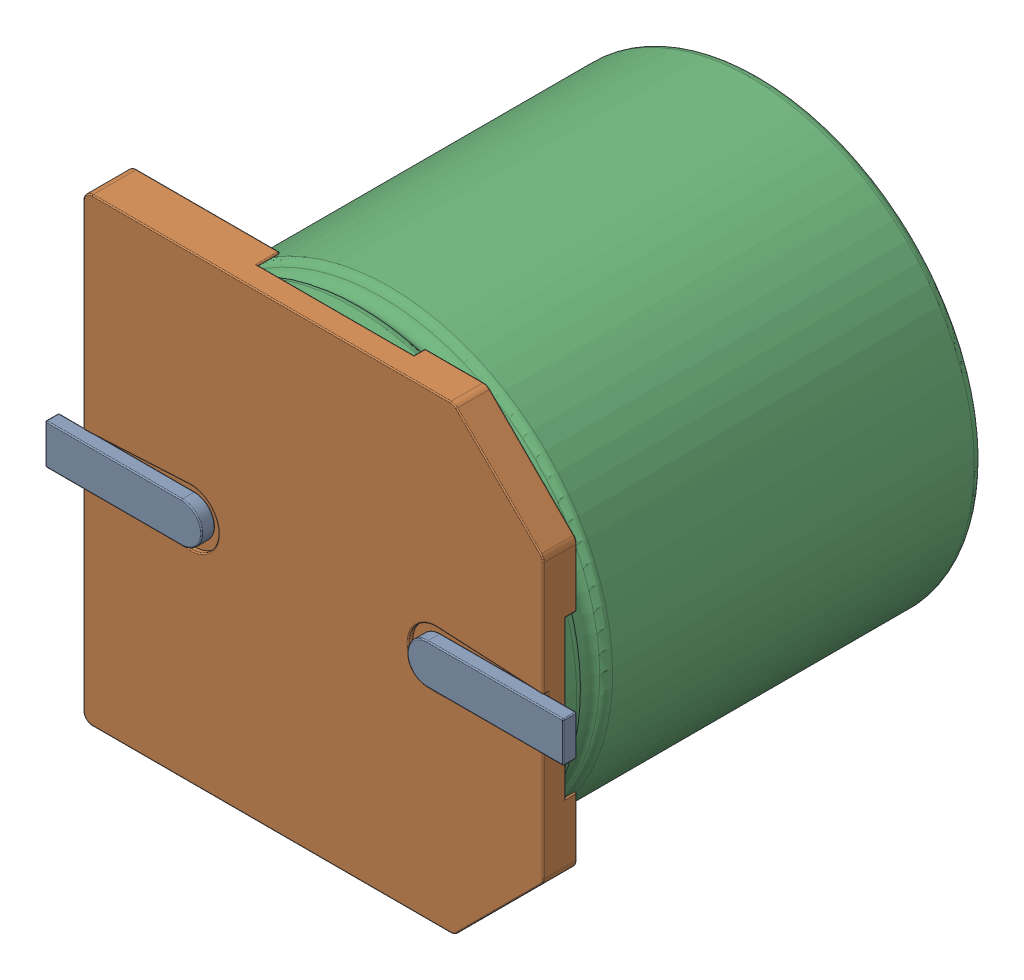
SolidWorks assembly C30, configuration Default. Lengths in mm.
Overall size (11.6 10.3 10.2).
5 component instances, 4 part files, 0 mates.
Components (placement in the parent):
- User_Library-ALU-G-1: User_Library-ALU-G [Default] at (26.6701 28.5749 -1.6914) x (1 0 0) z (0 0 -1) size (11.6 10.3 10.2)
  - Pins_1-1: Pins_1 [Default] at origin size (11.6 0.9 0.35)
  - Fuss_1-1: Fuss_1 [Default] at origin size (10.3 10.3 1)
  - K_X_F6rper_1-1: K_X_F6rper_1 [Default] at origin size (10 10 9.5)
  - Beschriftung_1-1: Beschriftung_1 [Default] at origin size (7.49 8.07 0.06)
